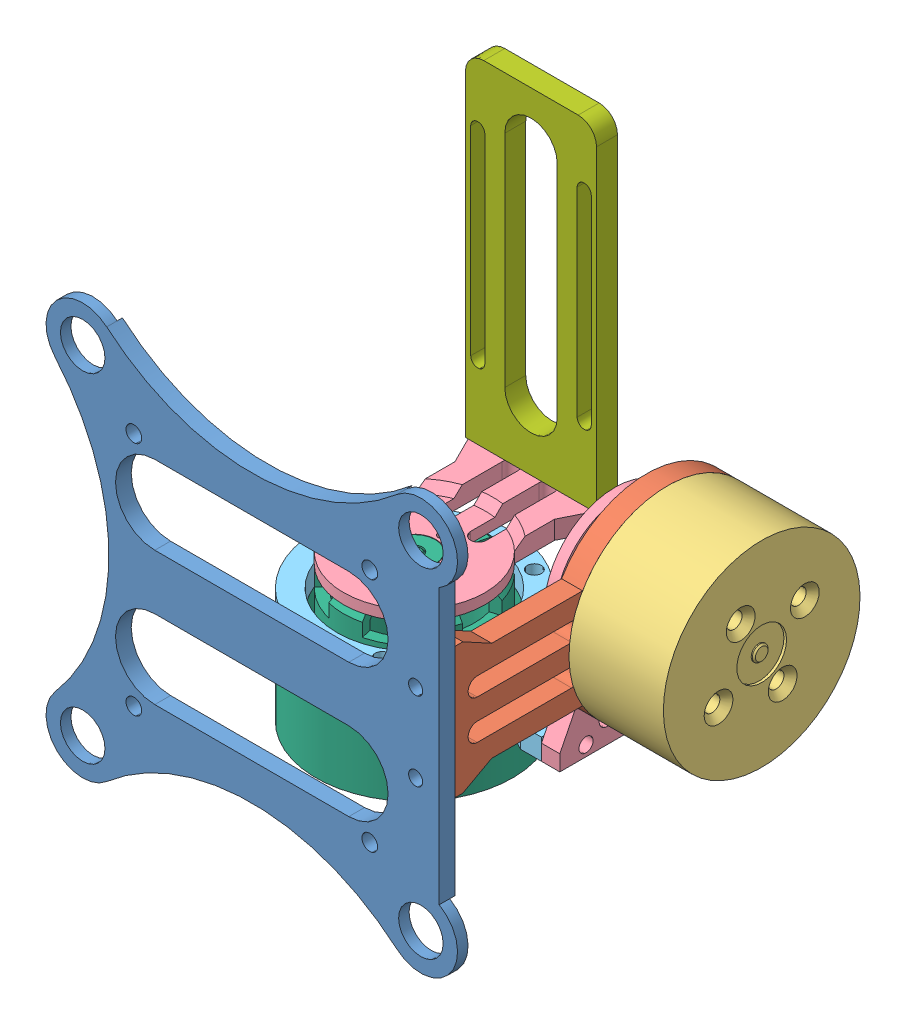
SolidWorks assembly Gimbal, configuration Default. Lengths in mm.
Overall size (91.86 93.5 72.25).
8 component instances, 7 part files, 0 mates.
Components (placement in the parent):
- Bottom Support Plate-1: Bottom Support Plate [Default] at (0 0 -19) x (1 0 0) z (0 -1 0) size (78.5 3 78.5)
- Roll Bracket-1: Roll Bracket [Default] at (31.25 0 -62) x (0 -1 0) z (-1 0 0) size (37.5 61.75 4)
- Motor-1: Motor [Default] at (51.25 0 -62) x (0 0.5 -0.866025) z (-1 0 0) size (37.5 37.5 28)
- Motor Bracket-1: Motor Bracket [Default] at (25.25 0 -62) x (0 -1 0) z (-1 0 0) size (39.75 27 3.5)
- Pitch Bracket-1: Pitch Bracket [Default] at (-15 -24.25 -62) x (0 0 1) z (0 1 0) size (37.5 55.5 4)
- Motor - OH-1: Motor - OH [Default] at (-15 -44.25 -62) x (0.866025 0 -0.5) z (0 1 0) size (37.5 37.5 28)
- Motor Bracket-2: Motor Bracket [Default] at (-15 -18.25 -62) x (0 0 -1) z (0 1 0) size (39.75 27 3.5)
- Camera Support-1: Camera Support [Default] at (-15 17.25 -86.25) x (1 0 0) z (0 1 0) size (25 4 64)
